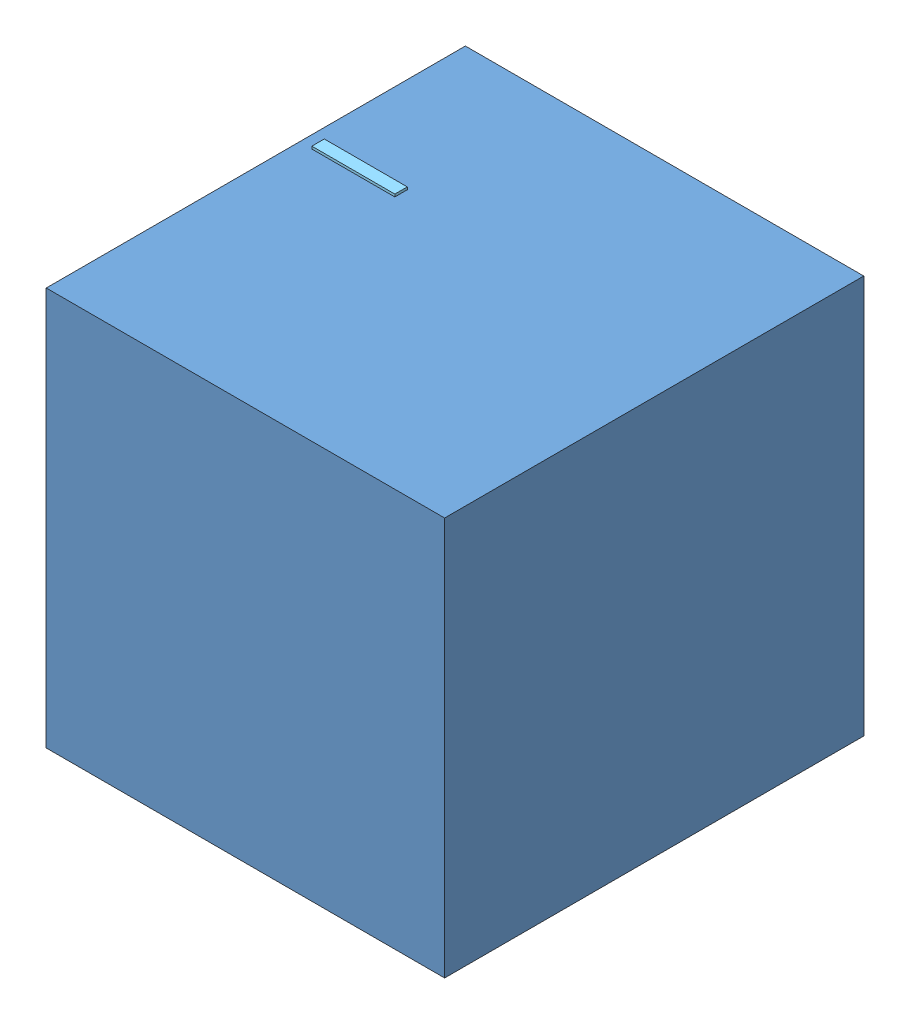
SolidWorks assembly Ensamblaje1, configuration Predeterminado. Lengths in mm.
Overall size (769.11 1236.04 891.7).
7 component instances, 7 part files, 25 mates.
Components (placement in the parent):
- Caja 2-1: Caja 2 [Predeterminado] at (-1416.3183 -598.759 505) size (480 480 505)
- Camino-1: Camino [Predeterminado] at (-1419.9184 -364.2918 246.5507) size (487.74 450 299.03)
- Camisa-1: Camisa [Predeterminado] at (-1291.3183 -358.759 581.5998) x (1 0 0) z (0 1 0) size (419.11 300 1056.57)
- Malla-1: Malla [Predeterminado] at (-1426.3183 -348.759 352.5) x (0 -1 0) z (0 0 1) size (487.74 450 299.03)
- Manija-1: Manija [Predeterminado] at (-1641.3183 -349.759 587.5) x (1 0 0) z (0 1 0) size (419.11 307.99 1136.7)
- Parlante-1: Parlante [Predeterminado] at (-1441.3183 -360.3441 583.752) x (1 0 0) z (0 1 0) size (528.67 372.23 1056.57)
- Switch-1: Switch [Predeterminado] at (-1541.3183 -360.3441 583.752) x (1 0 0) z (0 1 0) size (419.11 505.47 1236.04)
Mates (geometry in assembly coordinates):
- Coincidente4: coincident: plane of Caja 2-1 through (-1641.3183 -133.759 752.5) normal (1 0 0); plane of Manija-1 through (-1641.3183 -349.759 587.5) normal (-1 0 0)
- Coincidente5: coincident: plane of Caja 2-1 through (-1416.3183 -598.759 752.5) normal (0 0 -1); plane of Manija-1 through (-1541.3183 -574.759 737.5) normal (0 0 1)
- Coincidente6: coincident: line of Manija-1 through (-1541.3183 -583.759 452.5) axis (-1 0 0); line of Caja 2-1 through (-1191.3183 -583.759 452.5) axis (-1 0 0)
- Coincidente19: coincident: plane of Manija-1 through (-1541.3183 -349.759 587.5) normal (1 0 0); plane of Switch-1 through (-1541.3183 -360.3441 583.752) normal (-1 0 0)
- Paralelo5: parallel: line of Manija-1 through (-1541.3183 -124.759 737.5) axis (0 -1 0); plane of Switch-1 through (-1441.3183 -585.3441 733.752) normal (0 0 1)
- Paralelo6: parallel: line of Manija-1 through (-1541.3183 -124.759 737.5) axis (0 -1 0); line of Switch-1 through (-1541.3183 -135.3441 733.752) axis (0 -1 0)
- Paralelo7: parallel: line of Manija-1 through (-1541.3183 -124.759 737.5) axis (0 -1 0); line of Switch-1 through (-1541.3183 -135.3441 733.752) axis (0 -1 0)
- Coincidente25: coincident: plane of Manija-1 through (-1541.3183 -349.759 587.5) normal (1 0 0); plane of Switch-1 through (-1541.3183 -360.3441 583.752) normal (-1 0 0)
- Coincidente27: coincident: line of Manija-1 through (-1541.3183 -583.759 437.5) axis (0 1 0); plane of Switch-1 through (-1541.3183 -360.3441 583.752) normal (-1 0 0)
- Coincidente32: coincident: plane of Parlante-1 through (-1441.3183 -360.3441 583.752) normal (-1 0 0); plane of Switch-1 through (-1441.3183 -360.3441 583.752) normal (1 0 0)
- Coincidente33: coincident: plane of Parlante-1 through (-1441.3183 -360.3441 583.752) normal (-1 0 0); plane of Switch-1 through (-1441.3183 -360.3441 583.752) normal (1 0 0)
- Coincidente36: coincident: plane of Parlante-1 through (-1441.3183 -360.3441 583.752) normal (-1 0 0); plane of Switch-1 through (-1441.3183 -360.3441 583.752) normal (1 0 0)
- Coincidente40: coincident: plane of Parlante-1 through (-1441.3183 -360.3441 583.752) normal (-1 0 0); plane of Switch-1 through (-1441.3183 -360.3441 583.752) normal (1 0 0)
- Coincidente42: coincident: plane of Parlante-1 through (-1441.3183 -360.3441 583.752) normal (-1 0 0); plane of Switch-1 through (-1441.3183 -360.3441 583.752) normal (1 0 0)
- Coincidente51: coincident: point of Switch-1; point of Parlante-1
- Coincidente54: coincident: plane of Caja 2-1 through (-1191.3183 -133.759 752.5) normal (-1 0 0); line of Camisa-1 through (-1191.3183 -583.759 731.5998) axis (0 0 -1)
- Paralelo18: parallel: plane of Camisa-1 through (-1291.3183 -358.759 581.5998) normal (-1 0 0); plane of Parlante-1 through (-1341.3183 -360.3441 583.752) normal (1 0 0)
- Paralelo20: parallel: line of Camisa-1 through (-1291.3183 -592.759 431.5998) axis (0 1 0); line of Parlante-1 through (-1341.3183 -594.3441 433.752) axis (0 1 0)
- Coincidente64: coincident: plane of Caja 2-1 through (-1191.3183 -133.759 752.5) normal (-1 0 0); plane of Camisa-1 through (-1191.3183 -358.759 581.5998) normal (1 0 0)
- Coincidente65: coincident: plane of Caja 2-1 through (-1191.3183 -133.759 752.5) normal (-1 0 0); plane of Camisa-1 through (-1191.3183 -358.759 581.5998) normal (1 0 0)
- Coincidente66: coincident: plane of Caja 2-1 through (-1641.3183 -133.759 752.5) normal (0 -1 0); plane of Camisa-1 through (-1191.3183 -133.759 731.5998) normal (0 1 0)
- Coincidente67: coincident: plane of Caja 2-1 through (-1191.3183 -133.759 752.5) normal (-1 0 0); plane of Camisa-1 through (-1191.3183 -358.759 581.5998) normal (1 0 0)
- Paralelo21: parallel: line of Camisa-1 through (-1291.3183 -592.759 431.5998) axis (0 1 0); line of Parlante-1 through (-1341.3183 -594.3441 433.752) axis (0 1 0)
- Coincidente71: coincident: plane of Caja 2-1 through (-1181.3183 -123.759 452.5) normal (0 -1 0); plane of Malla-1 through (-1651.3183 -123.759 452.5) normal (0 1 0)
- Coincidente73: coincident: line of Caja 2-1 through (-1651.3183 -593.759 452.5) axis (0 1 0); line of Malla-1 through (-1651.3183 -123.759 452.5) axis (0 -1 0)
